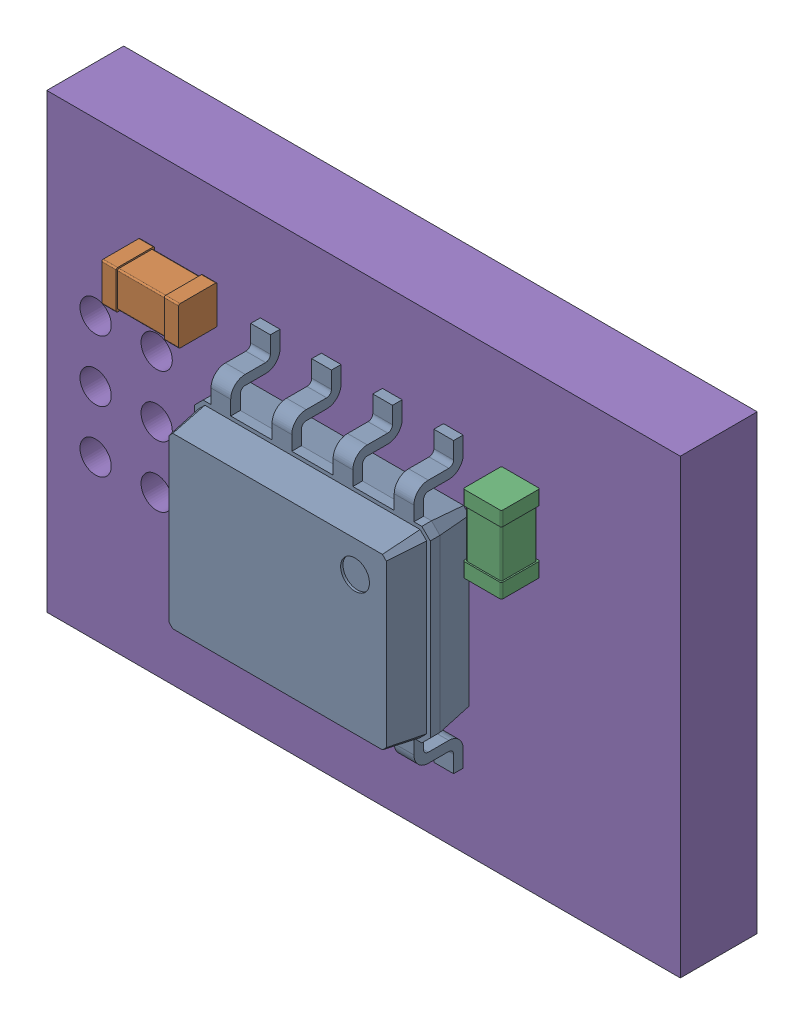
SolidWorks assembly AS5600-Hall-Sensor-PCB, configuration Default. Lengths in mm.
Overall size (13.18 9.4 3.9).
9 component instances, 4 part files, 0 mates.
Components (placement in the parent):
- SOIC-8_3.9x4.9mm_P1-1: SOIC-8_3.9x4.9mm_P1 [Default] at (159.255 110.49 0.05) x (0 -1 0) z (0 0 1) size (6 4.9 1.75)
  - SOLID_3-1: SOLID_3 [Default] at (110.617 -159.242 0) size (6 4.9 1.75)
- C_0603_1608Metric-1: C_0603_1608Metric [Default] at (155.448 113.284 0.05) x (-1 0 0) z (0 0 1) size (1.6 0.8 0.8)
  - SOLID_2-1: SOLID_2 [Default] at (159.242 110.617 0) size (1.6 0.8 0.8)
- C_0603_1608Metric (1)-1: C_0603_1608Metric (1) [Default] at (162.56 112.522 0.05) x (0 -1 0) z (0 0 1) size (1.6 0.8 0.8)
  - SOLID_2-1: SOLID_2 [Default] at (110.617 -159.242 0) size (1.6 0.8 0.8)
- PinHeader_2x03_P1-1: PinHeader_2x03_P1 [Default] at (154.94 111.76 -1.65) x (-1 0 0) z (0 0 -1) size (2 1.2 0.45)
  - SOLID-1: SOLID [Default] at (159.242 -110.617 0) size (2 1.2 0.45)
- COMPOUND2-1: COMPOUND2 [Default] at (-159.242 -110.617 0) x (1 0 0) z (0 0 -1) size (13.18 9.4 1.6)
